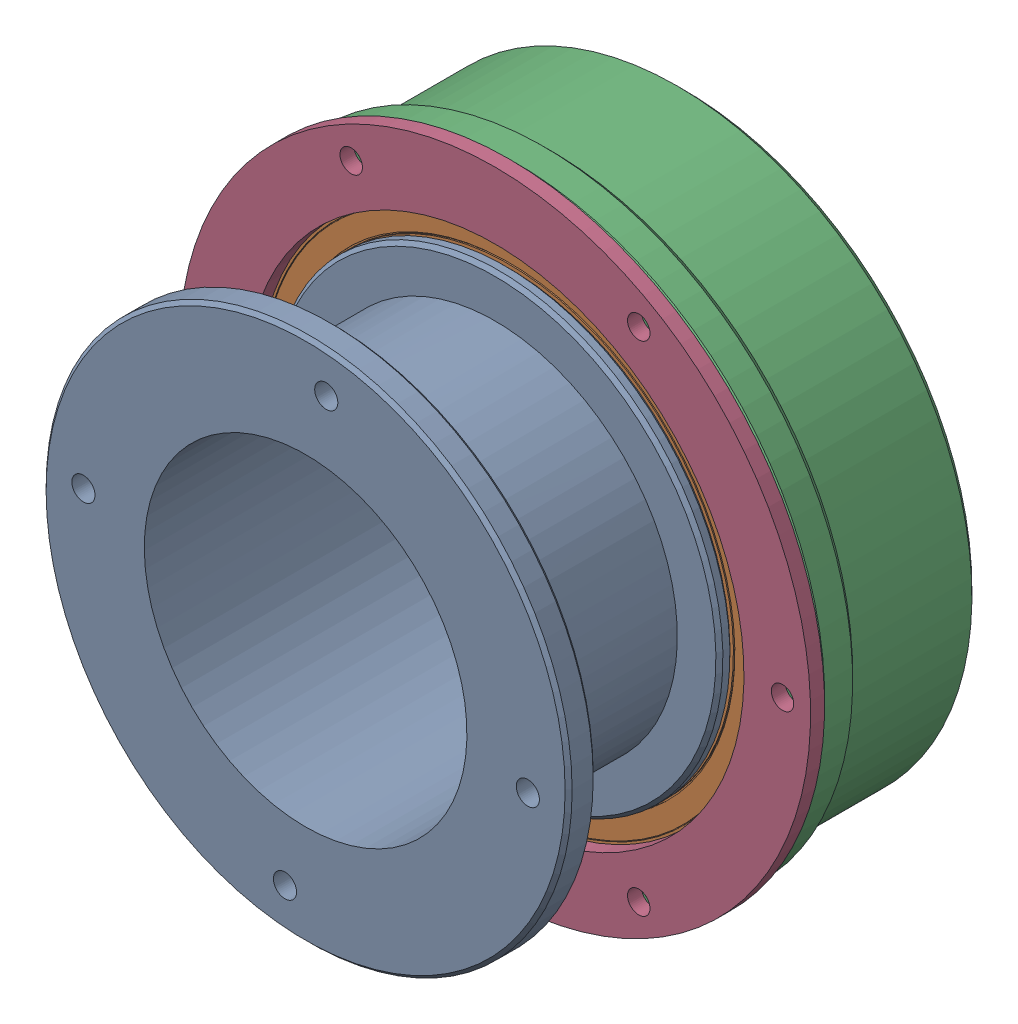
SolidWorks assembly 飞镖-底盘模块-交叉滚子轴承和它的朋友们-2020-12-1o, configuration 默认. Lengths in mm.
Overall size (122.94 122.94 54).
5 component instances, 5 part files, 11 mates.
Components (placement in the parent):
- 飞镖-交叉滚子轴承上轴承座-2020-11-26o-1: 飞镖-交叉滚子轴承上轴承座-2020-11-26o [默认] at (0 0 30) x (0.76948 0.638671 0) z (0 0 -1) size (75 75 37)
- 交叉滚子轴承-2020-11-25o-1: 交叉滚子轴承-2020-11-25o [默认] at (0 0 24) x (-0.02203 0.999757 0) z (-0.999757 -0.02203 0) size (76 8 76)
- 飞镖-底座模块-交叉滚子轴承座-2020-11-25o-1: 飞镖-底座模块-交叉滚子轴承座-2020-11-25o [默认] at (0 0 3) x (0.866025 -0.5 0) z (0 0 1) size (88 88 25)
- 飞镖-底座模块-交叉滚子轴承上固定板-2020-11-27o-1: 飞镖-底座模块-交叉滚子轴承上固定板-2020-11-27o [默认] at (0 0 28) x (0.866025 0.5 0) z (0 0 1) size (90 90 2)
- 飞镖-底盘模块-交叉滚子轴承玻纤垫块-2020-11-26o-1: 飞镖-底盘模块-交叉滚子轴承玻纤垫块-2020-11-26o [默认] at (0 0 18) x (-0.76948 -0.638671 0) z (0 0 1) size (63 63 2)
Mates (geometry in assembly coordinates):
- 同心3: concentric anti-aligned: cylinder of 交叉滚子轴承-2020-11-25-1 through (0 0 -36.4596) axis (0 0 -1) radius 38; cylinder of 飞镖-底座模块-交叉滚子轴承座-2020-11-25-1 through (0 0 20) axis (0 0 1) radius 38
- 同心4: concentric anti-aligned: cylinder of 飞镖-交叉滚子轴承上轴承座-2020-11-26o-1 through (0 0 20) axis (0 0 1) radius 23; cylinder of 交叉滚子轴承-2020-11-25-1 through (0 0 -36.4596) axis (0 0 -1) radius 38
- 同心5: concentric aligned: cylinder of 飞镖-交叉滚子轴承上轴承座-2020-11-26o-1 through (0 0 53) axis (0 0 -1) radius 26; cylinder of 交叉滚子轴承-2020-11-25-1 through (0 0 -36.4596) axis (0 0 -1) radius 30
- 重合2: coincident anti-aligned: plane of 飞镖-交叉滚子轴承上轴承座-2020-11-26o-1 through (0 0 28) normal (0 0 -1); plane of 交叉滚子轴承-2020-11-25-1 through (-0.7754 35.1915 28) normal (0 0 1)
- 同心6: concentric aligned: cylinder of 飞镖-交叉滚子轴承上轴承座-2020-11-26o-1 through (9.1969 24.8529 20) axis (0 0 -1) radius 1.25; cylinder of 飞镖-底盘模块-交叉滚子轴承玻纤垫块-2020-11-26o-1 through (9.1969 24.8529 20) axis (0 0 -1) radius 1.6
- 同心7: concentric aligned: cylinder of 飞镖-交叉滚子轴承上轴承座-2020-11-26o-1 through (26.1217 4.4617 20) axis (0 0 -1) radius 1.25; cylinder of 飞镖-底盘模块-交叉滚子轴承玻纤垫块-2020-11-26o-1 through (26.1217 4.4617 20) axis (0 0 -1) radius 1.6
- 重合3: coincident anti-aligned: plane of 交叉滚子轴承-2020-11-25-1 through (-0.7754 35.1915 20) normal (0 0 -1); plane of 飞镖-底座模块-交叉滚子轴承座-2020-11-25-1 through (0 0 20) normal (0 0 1)
- 重合4: coincident anti-aligned: plane of 交叉滚子轴承-2020-11-25-1 through (-0.7094 32.1922 20) normal (0 0 -1); plane of 飞镖-底盘模块-交叉滚子轴承玻纤垫块-2020-11-26o-1 through (0 0 20) normal (0 0 1)
- 同心8: concentric anti-aligned: cylinder of 飞镖-底座模块-交叉滚子轴承座-2020-11-25-1 through (-41 0 28) axis (0 0 1) radius 1.25; cylinder of 飞镖-底座模块-交叉滚子轴承上固定板-2020-11-27-1 through (-41 0 30) axis (0 0 -1) radius 1.6
- 同心9: concentric anti-aligned: cylinder of 飞镖-底座模块-交叉滚子轴承座-2020-11-25-1 through (-20.5 -35.507 28) axis (0 0 1) radius 1.25; cylinder of 飞镖-底座模块-交叉滚子轴承上固定板-2020-11-27-1 through (-20.5 -35.507 30) axis (0 0 -1) radius 1.6
- 重合5: coincident anti-aligned: plane of 飞镖-底座模块-交叉滚子轴承座-2020-11-25-1 through (0 0 28) normal (0 0 1); plane of 飞镖-底座模块-交叉滚子轴承上固定板-2020-11-27-1 through (0 0 28) normal (0 0 -1)
